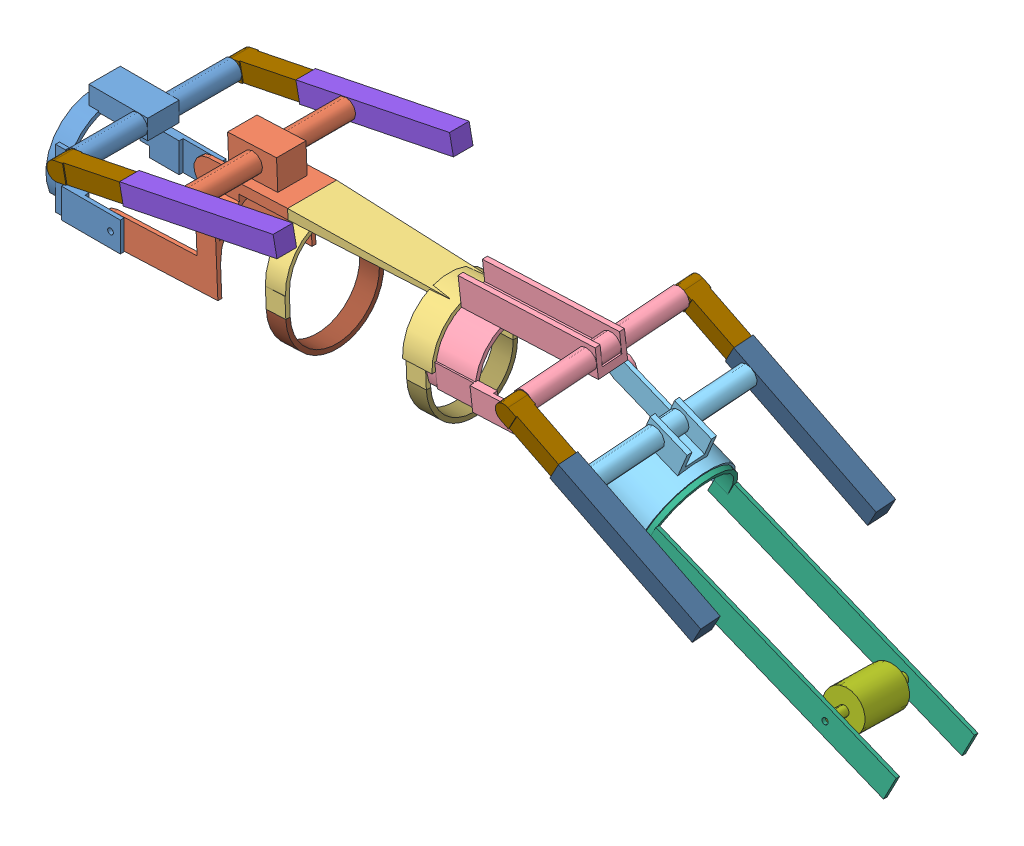
SolidWorks assembly arm, configuration Default. Lengths in mm.
Overall size (862.58 262.63 209.4).
18 component instances, 13 part files, 42 mates.
Components (placement in the parent):
- shoulder_arm_v0.1-1: shoulder_arm_v0.1 [Default] at (-0.3322 86.7785 124.2153) size (80 96 160)
- arm_p1_v0.2-1: arm_p1_v0.2 [Default] at (171.5821 146.2776 124.2153) x (-0.999089 -0.042665 0) z (0 0 -1) size (170 120.08 160)
- arm_p2_v0.1-1: arm_p2_v0.1 [Default] at (223.6698 98.4564 124.2153) x (-0.042665 0.999089 0) z (-0.999089 -0.042665 0) size (75 100 170)
- arm_p4-1: arm_p4 [Default] at (383.5241 105.2828 124.2153) x (-0.003128 0.07324 -0.997309) z (0.999089 0.042665 0) size (160 92.53 150)
- arm_p5_b_v0.1-1: arm_p5_b_v0.1 [Default] at (598.7183 60.9329 120.2835) x (0.003128 -0.07324 0.997309) z (-0.909259 0.414896 0.03332) size (160 85 130)
- arm_p5_a_v0.1-1: arm_p5_a_v0.1 [Default] at (575.9868 71.3053 121.1165) x (0.082877 0.102014 0.991325) z (0.407897 0.904132 -0.127142) size (92 275 58)
- hand_controller_v0.0-1: hand_controller_v0.0 [Default] at (776.0237 -19.9717 113.7861) x (0.082877 0.102014 0.991325) z (0.938271 -0.343202 -0.043123) size (84 40 40)
- arm_pole_a_v0.1-1: arm_pole_a_v0.1 [Default] at (263.926 184.2882 34.2153) x (-0.199151 0.979969 0) z (0 0 1) size (20 160 20)
- arm_pole_b_v0.1-1: arm_pole_b_v0.1 [Default] at (227.2424 176.8333 34.2153) x (0 0 -1) z (-0.199151 0.979969 0) size (20 180 18)
- arm_pole_a_v0.1-2: arm_pole_a_v0.1 [Default] at (263.926 184.2882 214.2153) x (0.199151 -0.979969 0) z (0 0 -1) size (20 160 20)
- arm_pole_b_v0.1-2: arm_pole_b_v0.1 [Default] at (227.2424 176.8333 214.2153) x (0 0 -1) z (-0.199151 0.979969 0) size (20 180 18)
- arm_pole_b_v0.1-3: arm_pole_b_v0.1 [Default] at (669.2871 91.0847 32.0337) x (-0.003128 0.07324 -0.997309) z (0.494494 0.866959 0.062116) size (20 180 18)
- arm_pole_b_v0.1-4: arm_pole_b_v0.1 [Default] at (669.8501 77.9016 211.5494) x (-0.003128 0.07324 -0.997309) z (0.494494 0.866959 0.062116) size (20 180 18)
- arm_pole_c_v0.1-1: arm_pole_c_v0.1 [Default] at (691.0485 78.7424 31.059) x (0.494494 0.866959 0.062116) z (0.003128 -0.07324 0.997309) size (20 160 20)
- arm_pole_c_v0.1-2: arm_pole_c_v0.1 [Default] at (691.6115 65.5592 210.5747) x (-0.494494 -0.866959 -0.062116) z (-0.003128 0.07324 -0.997309) size (20 160 20)
- back_100-1: back_100 [Default] at (224.5231 78.4746 124.2153) x (0 0 1) z (-0.042665 0.999089 0) size (100 20 50)
- back_84-1: back_84 [Default] at (384.3774 85.301 124.2153) x (0 0 -1) z (-0.999089 -0.042665 0) size (93 46.5 20)
- back_r42-1: back_r42 [Default] at (566.4459 62.4968 120.4996) x (-0.003128 0.07324 -0.997309) z (0.41622 0.906916 0.065296) size (96 20 48)
Mates (geometry in assembly coordinates):
- 重合1: coincident aligned: plane of shoulder_arm_v0.1-1 through (19.6678 116.7785 174.2153) normal (0 0 1); plane of arm_p1_v0.2-1 through (152.6704 120.364 174.2153) normal (0 0 1)
- 重合2: coincident anti-aligned: plane of arm_p1_v0.2-1 through (221.5365 148.4108 124.2153) normal (0.999089 0.042665 0); plane of arm_p2_v0.1-1 through (223.6698 98.4564 124.2153) normal (-0.999089 -0.042665 0)
- 重合3: coincident anti-aligned: line of arm_p1_v0.2-1 through (221.3232 153.4063 99.2153) axis (0 0 1); line of arm_p2_v0.1-1 through (221.3232 153.4063 149.2153) axis (0 0 -1)
- 重合4: coincident: plane of arm_p1_v0.2-1 through (151.8136 140.4288 99.2153) normal (0 0 -1); line of arm_p2_v0.1-1 through (221.3232 153.4063 99.2153) axis (0.042665 -0.999089 0)
- 同心3: concentric aligned: cylinder of arm_p2_v0.1-1 through (393.515 105.7094 124.2153) axis (-0.999089 -0.042665 0) radius 46; cylinder of arm_p4-1 through (433.4786 107.416 124.2153) axis (-0.999089 -0.042665 0) radius 42
- 重合5: coincident anti-aligned: plane of arm_p2_v0.1-1 through (383.5241 105.2828 124.2153) normal (0.999089 0.042665 0); plane of arm_p4-1 through (383.5241 105.2828 124.2153) normal (-0.999089 -0.042665 0)
- 重合6: coincident aligned: plane of arm_p4-1 through (452.8059 123.5952 79.2187) normal (-0.003128 0.07324 -0.997309); plane of arm_p5_b_v0.1-1 through (475.3761 107.3554 77.9554) normal (-0.003128 0.07324 -0.997309)
- 同心5: concentric anti-aligned: cylinder of arm_p5_b_v0.1-1 through (589.6257 65.0819 120.6167) axis (0.909259 -0.414896 -0.03332) radius 46; cylinder of arm_p5_a-1 through (603.2646 58.8585 120.1169) axis (-0.909259 0.414896 0.03332) radius 42
- 重合7: coincident anti-aligned: plane of arm_p5_b_v0.1-1 through (589.6257 65.0819 120.6167) normal (0.909259 -0.414896 -0.03332); plane of arm_p5_a-1 through (613.9104 113.4684 180.8128) normal (-0.909259 0.414896 0.03332)
- 同心6: concentric anti-aligned: cylinder of arm_p5_a-1 through (772.2114 -24.6644 68.1851) axis (0.082877 0.102014 0.991325) radius 3; cylinder of hand_controller-1 through (779.5045 -15.6871 155.4217) axis (-0.082877 -0.102014 -0.991325) radius 5
- 重合8: coincident anti-aligned: plane of arm_p5_a-1 through (599.7837 54.5739 78.4813) normal (0.082877 0.102014 0.991325); plane of hand_controller-1 through (772.5429 -24.2563 72.1504) normal (-0.082877 -0.102014 -0.991325)
- 同心8: concentric anti-aligned: cylinder of shoulder_arm_v0.1-1 through (59.6678 142.7785 204.2153) axis (0 0 -1) radius 10; cylinder of arm_pole_b_v0.1-1 through (59.6678 142.7785 24.2153) axis (0 0 1) radius 9
- 重合14: coincident anti-aligned: plane of shoulder_arm_v0.1-1 through (59.6678 142.7785 44.2153) normal (0 0 -1); plane of arm_pole_b_v0.1-1 through (52.6404 132.1664 44.2153) normal (0 0 1)
- 同心10: concentric aligned: cylinder of arm_p1_v0.2-1 through (175.7288 166.3646 44.2153) axis (0 0 1) radius 10; cylinder of arm_pole_a_v0.1-1 through (175.7288 166.3646 42.2153) axis (0 0 1) radius 3
- 重合15: coincident anti-aligned: plane of arm_p1_v0.2-1 through (175.7288 166.3646 44.2153) normal (0 0 -1); plane of arm_pole_a_v0.1-1 through (128.7219 146.6074 44.2153) normal (0 0 1)
- 重合16: coincident anti-aligned: plane of arm_pole_a_v0.1-1 through (124.938 165.2268 25.2153) normal (0.199151 -0.979969 0); plane of arm_pole_b_v0.1-1 through (68.6551 153.7889 43.2153) normal (-0.199151 0.979969 0)
- 同心11: concentric anti-aligned: cylinder of arm_p1_v0.2-1 through (175.7288 166.3646 44.2153) axis (0 0 1) radius 10; circle of arm_pole_a_v0.1-2
- 重合17: coincident anti-aligned: plane of arm_p1_v0.2-1 through (175.7288 166.3646 204.2153) normal (0 0 1); plane of arm_pole_a_v0.1-2 through (124.7389 166.2067 204.2153) normal (0 0 -1)
- 同心12: concentric anti-aligned: cylinder of shoulder_arm_v0.1-1 through (59.6678 142.7785 204.2153) axis (0 0 -1) radius 10; cylinder of arm_pole_b_v0.1-2 through (59.6678 142.7785 204.2153) axis (0 0 1) radius 9
- 重合18: coincident anti-aligned: plane of shoulder_arm_v0.1-1 through (59.6678 142.7785 204.2153) normal (0 0 1); plane of arm_pole_b_v0.1-2 through (52.6404 132.1664 204.2153) normal (0 0 -1)
- 重合19: coincident anti-aligned: plane of arm_pole_a_v0.1-2 through (124.938 165.2268 223.2153) normal (0.199151 -0.979969 0); plane of arm_pole_b_v0.1-2 through (68.6551 153.7889 223.2153) normal (-0.199151 0.979969 0)
- 同心13: concentric aligned: cylinder of arm_p4-1 through (520.6894 174.6501 48.6635) axis (0.003128 -0.07324 0.997309) radius 10; cylinder of arm_pole_b_v0.1-3 through (520.6269 176.1149 28.7173) axis (0.003128 -0.07324 0.997309) radius 9
- 重合20: coincident anti-aligned: plane of arm_p4-1 through (520.6894 174.6501 48.6635) normal (-0.003128 0.07324 -0.997309); plane of arm_pole_b_v0.1-3 through (508.4164 171.2842 48.4548) normal (0.003128 -0.07324 0.997309)
- 同心16: concentric aligned: cylinder of arm_p4-1 through (520.6894 174.6501 48.6635) axis (0.003128 -0.07324 0.997309) radius 10; cylinder of arm_pole_b_v0.1-4 through (521.1898 162.9318 208.233) axis (0.003128 -0.07324 0.997309) radius 9
- 同心17: concentric anti-aligned: cylinder of shoulder_arm_v0.1-1 through (69.6678 71.7785 44.2153) axis (0 0 1) radius 3; cylinder of arm_p1_v0.2-1 through (69.6678 71.7785 174.2153) axis (0 0 -1) radius 15
- 同心19: concentric aligned: cylinder of arm_p5_b_v0.1-1 through (587.2791 125.448 205.273) axis (-0.003128 0.07324 -0.997309) radius 10; circle of arm_pole_c_v0.1-1
- 重合27: coincident anti-aligned: plane of arm_p5_b_v0.1-1 through (586.7787 137.1663 45.7035) normal (-0.003128 0.07324 -0.997309); plane of arm_pole_c_v0.1-1 through (564.4503 138.3561 45.8609) normal (0.003128 -0.07324 0.997309)
- 重合28: coincident anti-aligned: plane of arm_pole_b_v0.1-3 through (525.7968 161.4981 46.6789) normal (-0.494494 -0.866959 -0.062116); plane of arm_pole_c_v0.1-1 through (564.8853 140.6146 26.9741) normal (0.494494 0.866959 0.062116)
- 同心20: concentric aligned: cylinder of arm_p5_b_v0.1-1 through (587.2791 125.448 205.273) axis (-0.003128 0.07324 -0.997309) radius 10; cylinder of arm_pole_c_v0.1-2 through (587.2854 125.3015 207.2676) axis (-0.003128 0.07324 -0.997309) radius 3
- 重合29: coincident anti-aligned: plane of arm_p5_b_v0.1-1 through (587.2791 125.448 205.273) normal (0.003128 -0.07324 0.997309); plane of arm_pole_c_v0.1-2 through (574.8406 143.9769 206.6727) normal (-0.003128 0.07324 -0.997309)
- 重合30: coincident anti-aligned: plane of arm_pole_b_v0.1-4 through (526.3598 148.3149 226.1946) normal (-0.494494 -0.866959 -0.062116); plane of arm_pole_c_v0.1-2 through (565.5046 126.1132 224.4414) normal (0.494494 0.866959 0.062116)
- 重合31: coincident anti-aligned: plane of arm_p4-1 through (521.1898 162.9318 208.233) normal (0.003128 -0.07324 0.997309); plane of arm_pole_b_v0.1-4 through (508.9168 159.5659 208.0243) normal (-0.003128 0.07324 -0.997309)
- 同心21: concentric anti-aligned: cylinder of arm_p4-1 through (491.1755 115.7498 44.4305) axis (0.003128 -0.07324 0.997309) radius 12; cylinder of arm_p5_b_v0.1-1 through (491.5759 106.3751 172.0862) axis (-0.003128 0.07324 -0.997309) radius 12
- 重合32: coincident anti-aligned: plane of arm_p2_v0.1-1 through (224.5231 78.4746 124.2153) normal (0.042665 -0.999089 0); plane of back_100-1 through (244.5049 79.3279 169.7153) normal (-0.042665 0.999089 0)
- 重合34: coincident aligned: line of arm_p2_v0.1-1 through (244.5049 79.3279 174.2153) axis (-0.999089 -0.042665 0); line of back_100-1 through (244.5049 79.3279 174.2153) axis (-0.999089 -0.042665 0)
- 重合35: coincident aligned: plane of arm_p2_v0.1-1 through (241.5183 149.2641 64.1003) normal (0.999089 0.042665 0); plane of back_100-1 through (244.5049 79.3279 124.2153) normal (0.999089 0.042665 0)
- 重合36: coincident aligned: plane of arm_p2_v0.1-1 through (361.409 154.384 64.1003) normal (-0.999089 -0.042665 0); plane of back_84-1 through (364.3956 84.4477 124.2153) normal (-0.999089 -0.042665 0)
- 重合37: coincident anti-aligned: line of arm_p2_v0.1-1 through (384.3774 85.301 170.7153) axis (-0.999089 -0.042665 0); line of back_84-1 through (364.3956 84.4477 170.7153) axis (0.999089 0.042665 0)
- 重合38: coincident anti-aligned: plane of arm_p2_v0.1-1 through (224.5231 78.4746 124.2153) normal (0.042665 -0.999089 0); plane of back_84-1 through (364.3956 84.4477 82.2153) normal (-0.042665 0.999089 0)
- 重合39: coincident anti-aligned: plane of arm_p5_b_v0.1-1 through (548.1106 74.3102 73.2951) normal (-0.41622 -0.906916 -0.065296); plane of back_r42-1 through (548.5414 64.2213 210.6772) normal (0.41622 0.906916 0.065296)
- 重合40: coincident aligned: plane of arm_p5_b_v0.1-1 through (553.2553 81.6777 121.9495) normal (-0.909259 0.414896 0.03332); plane of back_r42-1 through (548.6728 61.1452 252.5642) normal (-0.909259 0.414896 0.03332)
- 重合41: coincident aligned: line of arm_p5_b_v0.1-1 through (548.4108 67.2792 169.0368) axis (0.909259 -0.414896 -0.03332); line of back_r42-1 through (548.4108 67.2792 169.0368) axis (0.909259 -0.414896 -0.03332)
